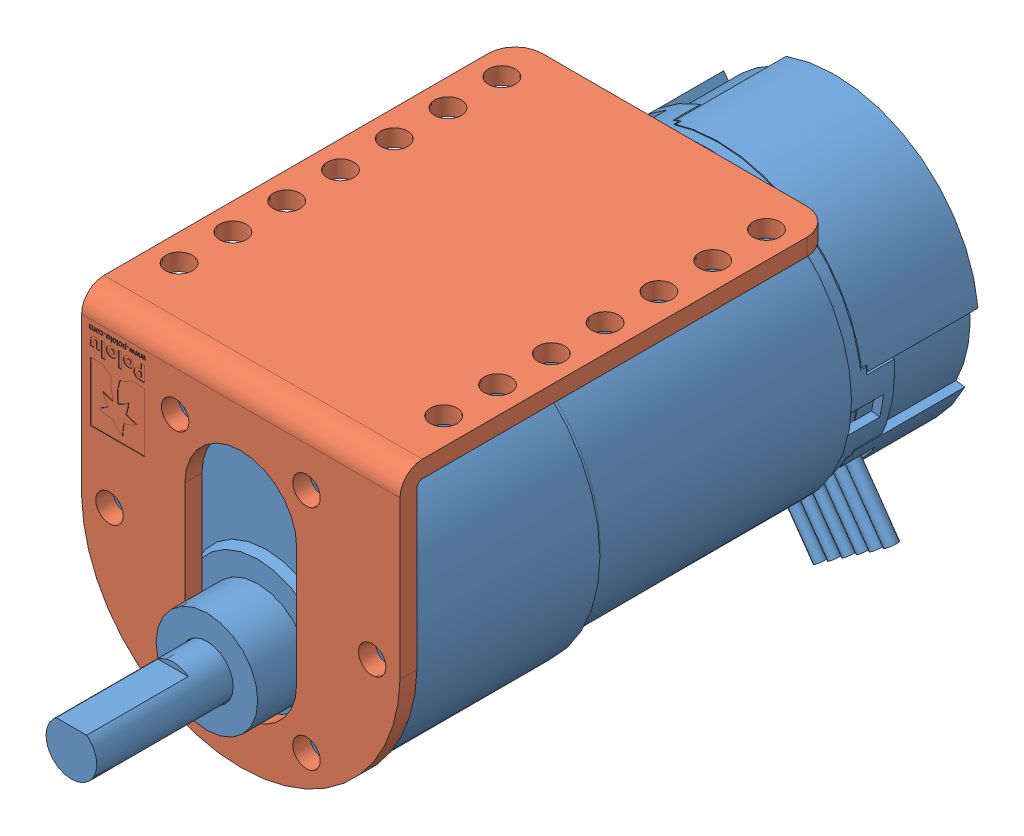
SolidWorks assembly Motor-bracket-wheel, configuration Default. Lengths in mm.
Overall size (90 90 98.85).
4 component instances, 4 part files, 7 mates.
Components (placement in the parent):
- 37d-gearmotor-19-30-encoder-1: 37d-gearmotor-19-30-encoder [Default] at (5.5166 54.4384 73.0499) size (36.88 41.23 90.1)
- pololu-stamped-aluminum-l-bracket-for-37d-mm-metal-gearmotors-1: pololu-stamped-aluminum-l-bracket-for-37d-mm-metal-gearmotors [Default] at (24.4372 55.4358 87.1749) x (-1 0 0) z (0 0 1) size (37.59 39.6 51.2)
- bigass wheel-1: bigass wheel [Default] at (25.4416 47.4384 119.9749) x (0.492367 -0.870388 0) z (0 0 1) (suppressed, hidden)
- pololu-wheel-90x10mm-red-1: pololu-wheel-90x10mm-red [Default] at (25.4416 47.4384 116.9749) x (0 0 -1) z (1 0 0) size (11.76 90 90)
Mates (geometry in assembly coordinates):
- Coincident1: coincident anti-aligned: plane of 37d-gearmotor-19-30-encoder-1 through (25.4416 54.4384 92.9749) normal (0 0 1); plane of pololu-stamped-aluminum-l-bracket-for-37d-mm-metal-gearmotors-1 through (6.6412 73.2358 92.9749) normal (0 0 -1)
- Concentric1: concentric anti-aligned: cylinder of 37d-gearmotor-19-30-encoder-1 through (33.1916 67.8617 90.1249) axis (0 0 1) radius 1.25; cylinder of pololu-stamped-aluminum-l-bracket-for-37d-mm-metal-gearmotors-1 through (33.1916 67.8617 92.9749) axis (0 0 -1) radius 1.6256
- Lock1: lock: unknown of 37d-gearmotor-19-30-encoder-1; unknown of pololu-stamped-aluminum-l-bracket-for-37d-mm-metal-gearmotors-1
- Distance1: distance = 25 mm anti-aligned: plane of pololu-stamped-aluminum-l-bracket-for-37d-mm-metal-gearmotors-1 through (6.6412 73.2358 94.9749) normal (0 0 1); plane of bigass wheel-1 through (25.4416 47.4384 119.9749) normal (0 0 -1)
- Concentric2: concentric aligned: cylinder of 37d-gearmotor-19-30-encoder-1 through (25.4416 47.4384 114.9749) axis (0 0 -1) radius 3; cylinder of bigass wheel-1 through (25.4416 47.4384 181.9749) axis (0 0 -1) radius 5
- Concentric3: concentric anti-aligned: circle of 37d-gearmotor-19-30-encoder-1; circle of pololu-wheel-90x10mm-red-1
- Distance2: distance = 19.5 mm anti-aligned: plane of pololu-wheel-90x10mm-red-1 through (25.4416 34.9384 114.4749) normal (0 0 -1); plane of pololu-stamped-aluminum-l-bracket-for-37d-mm-metal-gearmotors-1 through (6.6412 73.2358 94.9749) normal (0 0 1)
